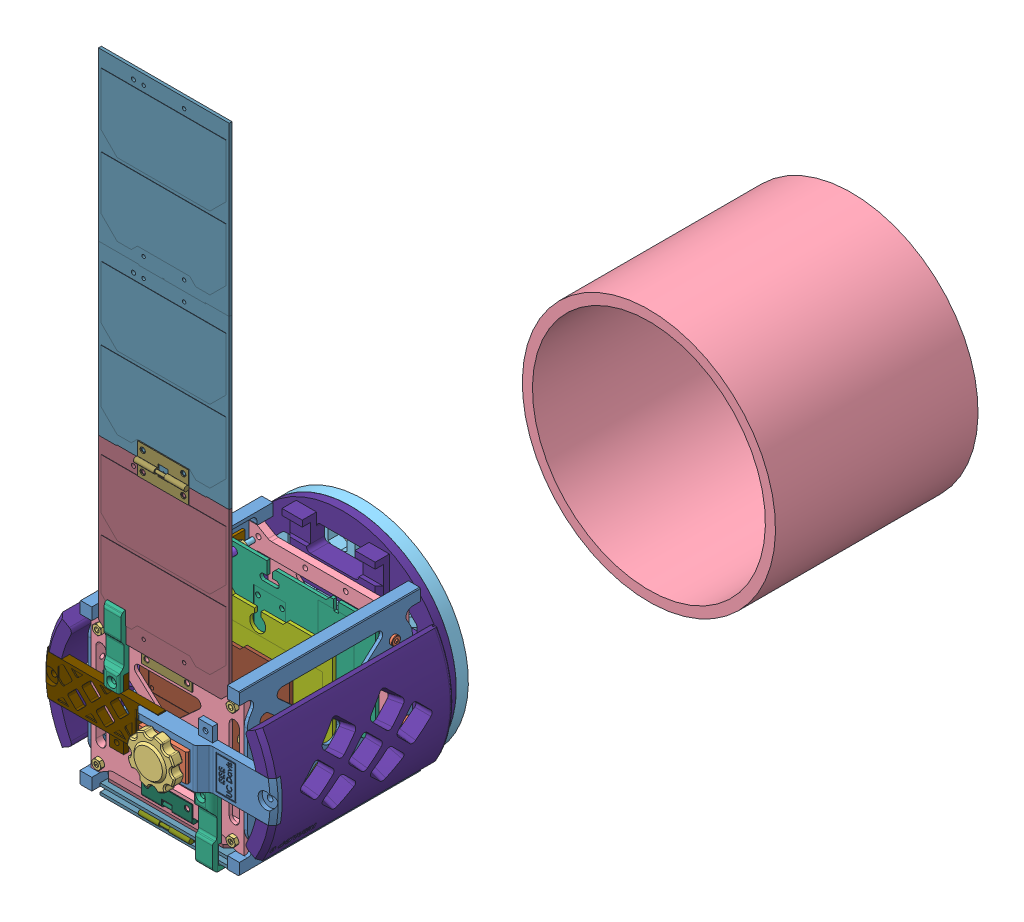
SolidWorks assembly 1U_Chassis, configuration Default. Lengths in mm.
Overall size (181.49 443.8 451.11).
71 component instances, 24 part files, 79 mates.
Components (placement in the parent):
- X-Face-1: X-Face [Default] at (6.5247 99.6979 78.5413) size (7.5 100 113.5)
- X-Face-2: X-Face [Default] at (106.5247 99.6979 78.5413) x (-1 0 0) z (0 0 1) size (7.5 100 113.5)
- 92855A309_18-8 Stainless Steel Low-Profile Socket Head Screws-1: 92855A309_18-8 Stainless Steel Low-Profile Socket Head Screws [92855A309] at (98.5247 117.1979 126.2913) x (0 0 1) z (-1 0 0) size (5.5 5.5 10.17)
- 90685A037_High-Strength Steel Hex Nut-1: 90685A037_High-Strength Steel Hex Nut [90685A037] at (100.3247 117.1979 126.2913) x (0 0 1) z (-1 0 0) size (5.5 6.35 2.69)
- 92855A309_18-8 Stainless Steel Low-Profile Socket Head Screws-2: 92855A309_18-8 Stainless Steel Low-Profile Socket Head Screws [92855A309] at (98.5247 82.1979 126.2913) x (0 0.91884 0.39463) z (-1 0 0) size (5.5 5.5 10.17)
- 90685A037_High-Strength Steel Hex Nut-2: 90685A037_High-Strength Steel Hex Nut [90685A037] at (100.8247 82.1979 126.2913) x (0 -0.924225 -0.381849) z (1 0 0) size (5.5 6.35 2.69)
- 92855A309_18-8 Stainless Steel Low-Profile Socket Head Screws-3: 92855A309_18-8 Stainless Steel Low-Profile Socket Head Screws [92855A309] at (98.5247 117.1979 30.7913) x (0 0.937066 0.349151) z (-1 0 0) size (5.5 5.5 10.17)
- 92855A309_18-8 Stainless Steel Low-Profile Socket Head Screws-4: 92855A309_18-8 Stainless Steel Low-Profile Socket Head Screws [92855A309] at (98.5247 82.1979 30.7913) x (0 0.549538 0.835469) z (-1 0 0) size (5.5 5.5 10.17)
- 90685A037_High-Strength Steel Hex Nut-3: 90685A037_High-Strength Steel Hex Nut [90685A037] at (103.4151 117.1979 30.7913) x (0 0 1) z (-1 0 0) size (5.5 6.35 2.69)
- 90685A037_High-Strength Steel Hex Nut-4: 90685A037_High-Strength Steel Hex Nut [90685A037] at (100.3247 82.1979 30.7913) x (0 0 1) z (-1 0 0) size (5.5 6.35 2.69)
- Z-Face-1: Z-Face [Default] at (56.5247 99.6979 26.7913) x (1 0 0) z (0 -1 0) size (96 8 84.8)
- Z-Face-2: Z-Face [Default] at (56.5247 99.6979 130.2913) x (-1 0 0) z (0 -1 0) size (96 8 84.8)
- 90685A037_High-Strength Steel Hex Nut-5: 90685A037_High-Strength Steel Hex Nut [90685A037] at (14.5247 136.1979 131.4913) x (-0.357096 -0.934068 0) z (0 0 -1) size (5.5 6.35 2.69)
- 90685A037_High-Strength Steel Hex Nut-6: 90685A037_High-Strength Steel Hex Nut [90685A037] at (14.5247 63.1979 131.8682) x (-0.923728 -0.383049 0) z (0 0 -1) size (5.5 6.35 2.69)
- 90685A037_High-Strength Steel Hex Nut-7: 90685A037_High-Strength Steel Hex Nut [90685A037] at (98.5247 136.1979 131.5827) x (-0.923728 -0.383049 0) z (0 0 -1) size (5.5 6.35 2.69)
- 90685A037_High-Strength Steel Hex Nut-8: 90685A037_High-Strength Steel Hex Nut [90685A037] at (98.5247 63.1979 131.646) x (-0.923728 -0.383049 0) z (0 0 -1) size (5.5 6.35 2.69)
- 92855A309_18-8 Stainless Steel Low-Profile Socket Head Screws-5: 92855A309_18-8 Stainless Steel Low-Profile Socket Head Screws [92855A309] at (98.5247 130.1979 38.7913) x (0 -0.400827 -0.916154) z (-1 0 0) size (5.5 5.5 10.17)
- 92855A309_18-8 Stainless Steel Low-Profile Socket Head Screws-6: 92855A309_18-8 Stainless Steel Low-Profile Socket Head Screws [92855A309] at (98.5247 69.1979 38.7913) x (0 0.663174 0.748465) z (-1 0 0) size (5.5 5.5 10.17)
- 90685A037_High-Strength Steel Hex Nut-9: 90685A037_High-Strength Steel Hex Nut [90685A037] at (98.5247 136.1979 41.6536) x (0.999336 0.036432 0) z (0 0 1) size (5.5 6.35 2.69)
- 90685A037_High-Strength Steel Hex Nut-10: 90685A037_High-Strength Steel Hex Nut [90685A037] at (14.5247 136.1979 42.0467) x (-0.999987 -0.005017 0) z (0 0 -1) size (5.5 6.35 2.69)
- 90685A037_High-Strength Steel Hex Nut-11: 90685A037_High-Strength Steel Hex Nut [90685A037] at (14.5247 63.1979 41.6778) x (0.999566 -0.029475 0) z (0 0 1) size (5.5 6.35 2.69)
- 90685A037_High-Strength Steel Hex Nut-12: 90685A037_High-Strength Steel Hex Nut [90685A037] at (98.5247 63.1979 41.599) x (0.999982 0.005949 0) z (0 0 1) size (5.5 6.35 2.69)
- PCB_Stack_3-1: PCB_Stack_3 [Default] at (98.5247 136.1979 34.7913) x (1 -0.000003 0) z (-0.000003 -1 0) size (96 95 83)
  - PCB_Rod_2-1: PCB_Rod_2 [Default] at origin size (3 95 3)
  - PCB_Rod_2-2: PCB_Rod_2 [Default] at (-84 0 0.0003) x (-0.139284 0 0.990253) z (-0.990253 0 -0.139284) size (3 95 3)
  - PCB_Rod_2-3: PCB_Rod_2 [Default] at (-83.9998 0 73.0003) x (0.037489 0 0.999297) z (-0.999297 0 0.037489) size (3 95 3)
  - PCB_Rod_2-4: PCB_Rod_2 [Default] at (0.0002 0 73) x (0.981991 0 -0.188925) z (0.188925 0 0.981991) size (3 95 3)
  - PCB_Battery-1: PCB_Battery [Default] at (-41.9999 10 36.5001) x (-1 0 0.000003) z (-0.000003 0 -1) size (94 2 83)
  - PCB-2: PCB [Default] at (-41.9999 37 36.5001) x (1 0 -0.000003) z (0.000003 0 1) size (94 2 83)
  - Aluminum Unthreaded Spacer_Battery-1: Aluminum Unthreaded Spacer_Battery [94669A105] at (0 24.5 0) x (0.317635 0 -0.948213) z (0 1 0) size (4.5 4.5 25)
  - Aluminum Unthreaded Spacer_Battery-2: Aluminum Unthreaded Spacer_Battery [94669A105] at (0 51.5 0) x (0.317635 0 -0.948213) z (0 1 0) size (4.5 4.5 25)
  - Aluminum Unthreaded Spacer_Battery-3: Aluminum Unthreaded Spacer_Battery [94669A105] at (0 78.5 0) x (-0.841831 0 -0.539741) z (0 1 0) size (4.5 4.5 25)
  - Aluminum Unthreaded Spacer_Battery-4: Aluminum Unthreaded Spacer_Battery [94669A105] at (0.0002 24.5 73) x (0.317635 0 -0.948213) z (0 1 0) size (4.5 4.5 25)
  - Aluminum Unthreaded Spacer_Battery-5: Aluminum Unthreaded Spacer_Battery [94669A105] at (0.0002 51.5 73) x (0.317635 0 -0.948213) z (0 1 0) size (4.5 4.5 25)
  - Aluminum Unthreaded Spacer_Battery-6: Aluminum Unthreaded Spacer_Battery [94669A105] at (0.0002 78.5 73) x (-0.286549 0 -0.958066) z (0 1 0) size (4.5 4.5 25)
  - Aluminum Unthreaded Spacer_Battery-7: Aluminum Unthreaded Spacer_Battery [94669A105] at (-83.9998 24.5 73.0003) x (0.317635 0 -0.948213) z (0 1 0) size (4.5 4.5 25)
  - Aluminum Unthreaded Spacer_Battery-8: Aluminum Unthreaded Spacer_Battery [94669A105] at (-83.9998 51.5 73.0003) x (0.317635 0 -0.948213) z (0 1 0) size (4.5 4.5 25)
  - Aluminum Unthreaded Spacer_Battery-9: Aluminum Unthreaded Spacer_Battery [94669A105] at (-83.9998 78.5 73.0003) x (-0.883236 0 -0.468929) z (0 1 0) size (4.5 4.5 25)
  - Aluminum Unthreaded Spacer_Battery-10: Aluminum Unthreaded Spacer_Battery [94669A105] at (-84 51.5 0.0003) x (0.317635 0 -0.948213) z (0 1 0) size (4.5 4.5 25)
  - Aluminum Unthreaded Spacer_Battery-11: Aluminum Unthreaded Spacer_Battery [94669A105] at (-84 78.5 0.0003) x (-0.872408 0 -0.488777) z (0 1 0) size (4.5 4.5 25)
  - Aluminum Unthreaded Spacer_Battery-12: Aluminum Unthreaded Spacer_Battery [94669A105] at (-84 24.5 0.0003) x (0.317635 0 -0.948213) z (0 1 0) size (4.5 4.5 25)
  - 88805K144_Architectural 6063 Aluminum 90 Degree Angle-1: 88805K144_Architectural 6063 Aluminum 90 Degree Angle [88805K144] at (-85.2375 5.2375 3.0003) x (-1 0 0.000003) z (0.000003 0 1) size (9.53 9.53 13)
  - 88805K144_Architectural 6063 Aluminum 90 Degree Angle-2: 88805K144_Architectural 6063 Aluminum 90 Degree Angle [88805K144] at (1.2377 5.2375 70) x (0 1 0) z (0.000003 0 1) size (9.53 9.53 13)
  - PCB_Bracket_1_(88805K144_Architectural 6063 Aluminum 90 Degree Angle)-1: PCB_Bracket_1_(88805K144_Architectural 6063 Aluminum 90 Degree Angle) [88805K144] at (1.2375 5.2375 3) x (0 1 0) z (0.000003 0 1) size (9.53 9.53 13)
  - PCB_Bracket_1_(88805K144_Architectural 6063 Aluminum 90 Degree Angle)-2: PCB_Bracket_1_(88805K144_Architectural 6063 Aluminum 90 Degree Angle) [88805K144] at (-85.2373 5.2375 70.0003) x (0 1 0) z (-0.000003 0 -1) size (9.53 9.53 13)
  - PCB2-1: PCB2 [Default] at (-41.9999 64 36.5001) x (1 0 -0.000003) z (0.000003 0 1) size (94 2 83)
- 90685A037_High-Strength Steel Hex Nut-13: 90685A037_High-Strength Steel Hex Nut [90685A037] at (11.3122 130.1979 38.7913) x (0 0.17998 -0.98367) z (1 0 0) size (5.5 6.35 2.69)
- COTS_OPEN-1: COTS_OPEN [Default] at (85.632 135.5476 144.7949) x (0 1 0) z (-1 0 0) size (322.55 8.13 82)
  - COTS_STS1114_180-1: COTS_STS1114_180 [Default] at (-5.3531 13.9448 13.2324) size (19.13 3.17 31.75)
  - SP_Imperial_COTS_Hinge_BASE-1: SP_Imperial_COTS_Hinge_BASE [Default] at (54.6417 13.9448 29.1074) x (-1 0 0) z (0 -1 0) size (105.41 82 1.98)
  - COTS_STS1114_180-2: COTS_STS1114_180 [Default] at (116.6685 12.1668 13.2324) x (-1 0 0) z (0 0 1) size (19.13 3.17 31.75)
  - Solar_Panel_FULL_Imperial_COTS_Hinge-1: Solar_Panel_FULL_Imperial_COTS_Hinge [Default] at (159.5691 13.9448 29.1074) x (-1 0 0) z (0 -1 0) size (105.41 82 1.98)
  - COTS_STS1114_180-3: COTS_STS1114_180 [Default] at (202.4697 13.9448 13.2324) size (19.13 3.17 31.75)
  - Solar_Panel_FULL_Imperial_COTS_Hinge-2: Solar_Panel_FULL_Imperial_COTS_Hinge [Default] at (264.4965 13.9448 29.1074) x (-1 0 0) z (0 -1 0) size (105.41 82 1.98)
- COTS_CLOSED-1: COTS_CLOSED [Default] at (82.4423 68.1791 105.3111) x (0 -1 0) z (-1 0 0) size (23.06 108.15 82)
  - COTS_STS1114_90-1: COTS_STS1114_90 [Default] at (8.5663 23.9515 10.0426) size (11.18 11.18 31.75)
  - SP_Imperial_COTS_Hinge_BASE-1: SP_Imperial_COTS_Hinge_BASE [Default] at (10.1538 -26.5056 25.9176) x (0 1 0) z (1 0 0) size (105.41 82 1.98)
  - COTS_STS1114_0-1: COTS_STS1114_0 [Default] at (13.5193 -78.9947 41.7926) x (1 0 0) z (0 0 -1) size (3.17 11.18 31.75)
  - Solar_Panel_FULL_Imperial_COTS_Hinge-1: Solar_Panel_FULL_Imperial_COTS_Hinge [Default] at (16.8848 -26.5056 25.9176) x (0 -1 0) z (-1 0 0) size (105.41 82 1.98)
  - COTS_STS1114_0-2: COTS_STS1114_0 [Default] at (18.4723 25.9835 10.0426) size (3.17 11.18 31.75)
  - Solar_Panel_FULL_Imperial_COTS_Hinge-2: Solar_Panel_FULL_Imperial_COTS_Hinge [Default] at (20.0598 -26.5056 25.9176) x (0 1 0) z (1 0 0) size (105.41 82 1.98)
- MountyThingy-1: MountyThingy [Default] at (56.5247 99.694 26.7913) x (0 -1 0) z (0 0 -1) size (132.08 144.9 120.51)
- ClampThingy-1: ClampThingy [Default] at (-5.4785 91.3199 190.3884) x (0 1 0) z (0 0 -1) size (43.18 145.58 21.82)
  - MountyThingyTop2-1: MountyThingyTop2 [Default] at (8.374 61.2013 54.5171) size (43.18 72.39 10.16)
  - MountyThingyTop1-1: MountyThingyTop1 [Default] at (8.374 62.0032 54.5171) size (43.18 83.94 10.16)
  - Wedge-1: Wedge [Default] at (-0.262 71.7622 52.1294) x (0 -1 0) z (1 0 0) size (30.86 5.08 17.27)
  - ThumbScrew-1: ThumbScrew [Default] at (8.374 72.1632 45.3984) x (-0.6464 0.762999 0) z (0 0 -1) size (29.63 29.63 12.45)
- Rochet-1: Rochet [Default] at (56.5247 99.694 -298.4986) x (0.987856 -0.155371 0) z (0 0 1) size (158.75 158.75 127)
- Insulator-1: Insulator [Default] at (56.5247 99.694 7.7413) x (-1 0 0) z (0 1 0) size (132.08 7.62 132.08)
- SolarPanelClamp-1: SolarPanelClamp [Default] at (79.532 78.104 130.7913) x (0 1 0) z (1 0 0) size (43.7 10.79 11.43)
- SolarPanelClamp-2: SolarPanelClamp [Default] at (32.7155 121.284 130.7913) x (0 -1 0) z (-1 0 0) size (43.7 10.79 11.43)
Mates (geometry in assembly coordinates):
- Coincident2: coincident anti-aligned: plane of X-Face-1 through (8.5247 57.1979 135.2913) normal (1 0 0); plane of S2-1 through (8.5247 142.1979 184.9271) normal (-1 0 0)
- Coincident3: coincident anti-aligned: plane of X-Face-1 through (8.5247 142.1979 135.2913) normal (0 -1 0); plane of S2-1 through (56.5247 142.1979 135.6771) normal (0 1 0)
- Coincident5: coincident anti-aligned: plane of S2-1 through (56.5247 142.1979 135.6771) normal (0 1 0); plane of X-Face-2 through (99.0247 142.1979 135.2913) normal (0 -1 0)
- Coincident6: coincident anti-aligned: plane of S2-1 through (104.5247 142.1979 184.9271) normal (1 0 0); plane of X-Face-2 through (104.5247 142.1979 135.2913) normal (-1 0 0)
- Coincident8: coincident anti-aligned: plane of X-Face-1 through (14.0247 57.1979 135.2913) normal (0 1 0); plane of S2-2 through (56.5247 57.1979 135.1691) normal (0 -1 0)
- Coincident9: coincident anti-aligned: plane of X-Face-1 through (8.5247 57.1979 135.2913) normal (1 0 0); plane of S2-2 through (8.5247 59.1979 184.4191) normal (-1 0 0)
- Coincident14: coincident aligned: plane of X-Face-1 through (14.0247 149.6979 135.2913) normal (0 1 0); plane of X-Face-2 through (106.5247 149.6979 135.2913) normal (0 1 0)
- Coincident16: coincident anti-aligned: plane of X-Face-1 through (8.5247 57.1979 135.2913) normal (1 0 0); plane of Z-2 through (8.5247 57.1979 130.2913) normal (-1 0 0)
- Coincident17: coincident aligned: plane of X-Face-1 through (6.5247 99.6979 130.2913) normal (0 0 1); plane of Z-2 through (104.5247 57.1979 130.2913) normal (0 0 1)
- Coincident18: coincident anti-aligned: plane of X-Face-1 through (14.0247 57.1979 135.2913) normal (0 1 0); plane of Z-2 through (56.5247 57.1979 128.2913) normal (0 -1 0)
- Concentric5: concentric aligned: cylinder of X-Face-2 through (106.5247 117.1979 126.2913) axis (-1 0 0) radius 1.5; cylinder of 92855A309_18-8 Stainless Steel Low-Profile Socket Head Screws-1 through (108.5247 117.1979 126.2913) axis (-1 0 0) radius 2.75
- Coincident19: coincident anti-aligned: plane of X-Face-2 through (106.5247 49.6979 135.2913) normal (1 0 0); plane of 92855A309_18-8 Stainless Steel Low-Profile Socket Head Screws-1 through (106.5247 117.1979 126.2913) normal (-1 0 0)
- Coincident21: coincident anti-aligned: circle of Z-2; circle of 90685A037_High-Strength Steel Hex Nut-1
- Concentric6: concentric aligned: circle of S1-2; circle of 92855A309_18-8 Stainless Steel Low-Profile Socket Head Screws-2
- Concentric7: concentric aligned: cylinder of X-Face-2 through (106.5247 82.1979 126.2913) axis (-1 0 0) radius 1.5; cylinder of 92855A309_18-8 Stainless Steel Low-Profile Socket Head Screws-2 through (108.5247 82.1979 126.2913) axis (-1 0 0) radius 2.75
- Coincident22: coincident anti-aligned: plane of X-Face-2 through (106.5247 49.6979 135.2913) normal (1 0 0); plane of 92855A309_18-8 Stainless Steel Low-Profile Socket Head Screws-2 through (106.5247 82.1979 126.2913) normal (-1 0 0)
- Coincident23: coincident anti-aligned: circle of Z-2; circle of 90685A037_High-Strength Steel Hex Nut-2
- Concentric8: concentric aligned: cylinder of X-Face-2 through (106.5247 117.1979 30.7913) axis (-1 0 0) radius 1.5; cylinder of 92855A309_18-8 Stainless Steel Low-Profile Socket Head Screws-3 through (108.5247 117.1979 30.7913) axis (-1 0 0) radius 2.75
- Coincident24: coincident anti-aligned: plane of X-Face-2 through (104.5247 142.1979 135.2913) normal (-1 0 0); plane of Z-2 through (104.5247 57.1979 120.7913) normal (1 0 0)
- Coincident25: coincident anti-aligned: plane of X-Face-2 through (106.5247 49.6979 135.2913) normal (1 0 0); plane of 92855A309_18-8 Stainless Steel Low-Profile Socket Head Screws-3 through (106.5247 117.1979 30.7913) normal (-1 0 0)
- Concentric9: concentric aligned: cylinder of X-Face-2 through (106.5247 82.1979 30.7913) axis (-1 0 0) radius 1.5; cylinder of 92855A309_18-8 Stainless Steel Low-Profile Socket Head Screws-4 through (108.5247 82.1979 30.7913) axis (-1 0 0) radius 2.75
- Coincident26: coincident anti-aligned: plane of X-Face-2 through (106.5247 49.6979 135.2913) normal (1 0 0); plane of 92855A309_18-8 Stainless Steel Low-Profile Socket Head Screws-4 through (106.5247 82.1979 30.7913) normal (-1 0 0)
- Coincident27: coincident anti-aligned: plane of X-Face-2 through (104.5247 142.1979 135.2913) normal (-1 0 0); plane of Z-Face-1 through (104.5247 57.2979 28.7913) normal (1 0 0)
- Distance1: distance = 0 mm aligned: plane of Z-Face-1 through (90.534 57.8699 26.7913) normal (0 0 -1); plane of X-Face-2 through (106.5247 99.6979 26.7913) normal (0 0 -1)
- Coincident34: coincident aligned: plane of X-Face-1 through (6.5247 99.6979 26.7913) normal (0 0 -1); plane of Z-Face-1 through (90.534 57.8699 26.7913) normal (0 0 -1)
- Coincident35: coincident: plane of Z-Face-1 through (90.534 57.8699 26.7913) normal (0 0 -1); plane of Hinge_Assembly-2/H2-3 through (44.0247 128.9479 26.7913) normal (0 0 1)
- Coincident36: coincident: cylinder of Z-Face-1 through (43.8247 133.7759 28.7913) axis (0 0 -1) radius 1.5; circle of Hinge_Assembly-2/H2-3
- Parallel3: parallel aligned: line of Z-Face-1 through (90.534 137.5259 26.7913) axis (-1 0 0); line of Hinge_Assembly-2/H2-3 through (79.0247 128.9479 25.0413) axis (-1 0 0)
- Coincident42: coincident anti-aligned: plane of X-Face-1 through (8.5247 57.1979 135.2913) normal (1 0 0); plane of Z-Face-2 through (8.5247 57.2979 128.2913) normal (-1 0 0)
- Coincident43: coincident aligned: plane of X-Face-1 through (6.5247 99.6979 130.2913) normal (0 0 1); plane of Z-Face-2 through (22.5154 57.8699 130.2913) normal (0 0 1)
- Concentric12: concentric anti-aligned: circle of 90685A037_High-Strength Steel Hex Nut-3; circle of Z2-1
- Concentric14: concentric aligned: circle of Z2-2; circle of 90685A037_High-Strength Steel Hex Nut-6
- Concentric15: concentric aligned: circle of Z2-2; circle of 90685A037_High-Strength Steel Hex Nut-7
- Concentric16: concentric aligned: circle of Z2-2; circle of 90685A037_High-Strength Steel Hex Nut-8
- Coincident50: coincident anti-aligned: plane of X-Face-2 through (106.5247 49.6979 135.2913) normal (1 0 0); plane of 92855A309_18-8 Stainless Steel Low-Profile Socket Head Screws-5 through (106.5247 130.1979 38.7913) normal (-1 0 0)
- Coincident51: coincident anti-aligned: plane of X-Face-2 through (106.5247 49.6979 135.2913) normal (1 0 0); plane of 92855A309_18-8 Stainless Steel Low-Profile Socket Head Screws-6 through (106.5247 69.1979 38.7913) normal (-1 0 0)
- Concentric24: concentric aligned: circle of Z-Face-2; circle of 90685A037_High-Strength Steel Hex Nut-5
- Coincident64: coincident anti-aligned: plane of Z-Face-2 through (22.5154 57.8699 130.2913) normal (0 0 1); plane of 90685A037_High-Strength Steel Hex Nut-5 through (14.5247 136.1979 130.2913) normal (0 0 -1)
- Concentric25: concentric anti-aligned: cylinder of X-Face-1 through (6.5247 117.1979 126.2913) axis (1 0 0) radius 1.5; cylinder of Z-Face-2 through (13.5247 117.1979 126.2913) axis (-1 0 0) radius 1.5
- Concentric26: concentric anti-aligned: cylinder of Z-Face-2 through (98.5247 63.1979 128.2913) axis (0 0 1) radius 1.5875; cylinder of PCB_Stack_3-1/PCB_Rod_2-4 through (98.5247 63.1979 129.7913) axis (0 0 -1) radius 1.5
- Coincident67: coincident anti-aligned: plane of Z-Face-2 through (56.5247 99.6979 125.7913) normal (0 0 -1); plane of PCB_Stack_3-1/Aluminum Unthreaded Spacer_Battery-3 through (98.5247 136.1979 125.7913) normal (0 0 1)
- Parallel10: parallel anti-aligned: line of X-Face-2 through (104.5247 119.8573 34.7913) axis (0 -1 0); line of PCB_Stack_3-1/PCB_Battery-1 through (103.5247 58.1979 46.7913) axis (0 1 0)
- Concentric27: concentric anti-aligned: circle of 90685A037_High-Strength Steel Hex Nut-10; circle of PCB_Stack_3-1/88805K144_Architectural 6063 Aluminum 90 Degree Angle-1
- Concentric28: concentric anti-aligned: circle of PCB_Stack_3-1/88805K144_Architectural 6063 Aluminum 90 Degree Angle-1; circle of 90685A037_High-Strength Steel Hex Nut-13
- Coincident68: coincident anti-aligned: plane of PCB_Stack_3-1/88805K144_Architectural 6063 Aluminum 90 Degree Angle-1 through (10.1122 126.6979 35.2663) normal (1 0 0); plane of 90685A037_High-Strength Steel Hex Nut-13 through (10.1122 130.1979 38.7913) normal (-1 0 0)
- Coincident69: coincident anti-aligned: circle of 90685A037_High-Strength Steel Hex Nut-9; cylinder of PCB_Stack_3-1/PCB_Rod_2-1 through (98.5247 136.1979 129.7913) axis (0 0 -1) radius 1.5
- Coincident70: coincident anti-aligned: circle of 90685A037_High-Strength Steel Hex Nut-12; cylinder of PCB_Stack_3-1/PCB_Rod_2-4 through (98.5247 63.1979 129.7913) axis (0 0 -1) radius 1.5
- Coincident71: coincident anti-aligned: circle of 90685A037_High-Strength Steel Hex Nut-11; cylinder of PCB_Stack_3-1/PCB_Rod_2-3 through (14.5247 63.1979 129.7913) axis (0 0 -1) radius 1.5
- Concentric29: concentric aligned: circle of X-Face-2; circle of 92855A309_18-8 Stainless Steel Low-Profile Socket Head Screws-5
- Concentric30: concentric aligned: circle of X-Face-2; circle of 92855A309_18-8 Stainless Steel Low-Profile Socket Head Screws-6
- Coincident72: coincident anti-aligned: plane of Z-Face-2 through (22.5154 57.8699 130.2913) normal (0 0 1); plane of COTS_OPEN-1/COTS_STS1114_180-1 through (40.6497 130.1945 130.2913) normal (0 0 -1)
- Concentric31: concentric aligned: cylinder of Z-Face-2 through (43.8247 133.7759 128.2913) axis (0 0 1) radius 1.5; circle of COTS_OPEN-1/COTS_STS1114_180-1
- Parallel11: parallel aligned: line of Z-Face-2 through (22.5154 137.5259 130.2913) axis (1 0 0); line of COTS_OPEN-1/COTS_STS1114_180-1 through (40.6497 130.1945 130.8501) axis (1 0 0)
- Coincident74: coincident anti-aligned: plane of Z-Face-2 through (22.5154 57.8699 130.2913) normal (0 0 1); plane of COTS_CLOSED-1/COTS_STS1114_90-1 through (40.6497 69.2013 130.2913) normal (0 0 -1)
- Concentric32: concentric aligned: cylinder of Z-Face-2 through (43.8247 65.6199 128.2913) axis (0 0 1) radius 1.5; circle of COTS_CLOSED-1/COTS_STS1114_90-1
- Parallel12: parallel anti-aligned: line of Z-Face-2 through (90.534 61.8699 130.2913) axis (-1 0 0); line of COTS_CLOSED-1/COTS_STS1114_90-1 through (40.6497 69.2013 130.8501) axis (1 0 0)
- Coincident75: coincident anti-aligned: plane of X-Face-1 through (8.5247 57.1979 135.2913) normal (1 0 0); plane of Z-Face-1 through (8.5247 57.2979 28.7913) normal (-1 0 0)
- Concentric33: concentric anti-aligned: cylinder of X-Face-1 through (6.5247 117.1979 30.7913) axis (1 0 0) radius 1.5; cylinder of Z-Face-1 through (13.5247 117.1979 30.7913) axis (-1 0 0) radius 1.5
- Coincident76: coincident anti-aligned: plane of X-Face-1 through (6.5247 49.6979 135.2913) normal (0 -1 0); plane of 88805K144_Architectural 6063 Aluminum 90 Degree Angle (1)-1 through (14.4622 49.6979 142.4093) normal (0 1 0)
- Coincident77: coincident anti-aligned: plane of X-Face-1 through (6.5247 149.6979 135.2913) normal (-1 0 0); plane of 88805K144_Architectural 6063 Aluminum 90 Degree Angle (1)-1 through (6.5247 49.6979 142.4093) normal (1 0 0)
- Coincident79: coincident: plane of X-Face-2 through (106.5247 149.6979 135.2913) normal (0 1 0); plane of 88805K144_Architectural 6063 Aluminum 90 Degree Angle (1)-2 through (98.5872 149.6979 154.433) normal (0 -1 0)
- Coincident80: coincident anti-aligned: plane of X-Face-2 through (106.5247 49.6979 135.2913) normal (1 0 0); plane of 88805K144_Architectural 6063 Aluminum 90 Degree Angle (1)-2 through (106.5247 149.6979 154.433) normal (-1 0 0)
- Coincident81: coincident anti-aligned: plane of Z-Face-1 through (90.534 57.8699 26.7913) normal (0 0 -1); plane of MountyThingy-1 through (42.5547 57.9999 26.7913) normal (0 0 1)
- Coincident82: coincident: point of MountyThingy-1; point of MountyThingyTop-1
- Concentric35: concentric anti-aligned: circle of MountyThingy-1; circle of MountyThingyTop-1
- Concentric36: concentric anti-aligned: circle of MountyThingy-1; circle of ClampThingy-1/MountyThingyTop1-1
- Coincident89: coincident anti-aligned: plane of MountyThingy-1 through (56.5247 99.694 130.7913) normal (0 0 1); plane of ClampThingy-1/MountyThingyTop1-1 through (56.5247 99.694 130.7913) normal (0 0 -1)
- Parallel14: parallel anti-aligned: line of MountyThingy-1 through (117.4184 112.521 135.8713) axis (1 0 0); line of ClampThingy-1/MountyThingyTop1-1 through (125.2104 112.394 135.8713) axis (-1 0 0)
- Concentric37: concentric anti-aligned: cylinder of MountyThingy-1 through (56.5247 99.694 20.4413) axis (0 0 1) radius 72.39; cylinder of Rochet-1 through (56.5247 99.694 -171.4986) axis (0 0 -1) radius 73.025
- Parallel16: parallel anti-aligned: line of Z-Face-1 through (90.534 137.5259 31.2913) axis (-1 0 0); line of MountyThingy-1 through (42.5547 138.8481 26.7913) axis (1 0 0)
- Coincident90: coincident anti-aligned: circle of MountyThingy-1; circle of Insulator-1
- Parallel17: parallel aligned: line of MountyThingy-1 through (18.4247 103.9398 15.3613) axis (0 -1 0); line of Insulator-1 through (25.483 88.5333 7.7413) axis (0 -1 0)
- Concentric38: concentric aligned: cylinder of Z-Face-1 through (43.8247 65.6199 28.7913) axis (0 0 -1) radius 1.5; circle of MountyThingy-1
- Concentric39: concentric anti-aligned: cylinder of ClampThingy-1/MountyThingyTop1-1 through (83.977 82.549 133.9663) axis (0 0 -1) radius 1.524; cylinder of SolarPanelClamp-1 through (83.977 82.549 126.3463) axis (0 0 1) radius 1.524
- Coincident92: coincident anti-aligned: plane of ClampThingy-1/MountyThingyTop1-1 through (88.422 86.994 133.9663) normal (1 0 0); plane of SolarPanelClamp-1 through (88.422 78.104 130.7913) normal (-1 0 0)
- Coincident93: coincident anti-aligned: plane of ClampThingy-1/MountyThingyTop1-1 through (56.5247 99.694 133.9663) normal (0 0 1); plane of SolarPanelClamp-1 through (90.962 78.104 133.9663) normal (0 0 -1)
- Concentric40: concentric anti-aligned: cylinder of ClampThingy-1/MountyThingyTop2-1 through (28.2705 116.839 133.9663) axis (0 0 -1) radius 1.524; cylinder of SolarPanelClamp-2 through (28.2705 116.839 126.3463) axis (0 0 1) radius 1.524
- Parallel18: parallel anti-aligned: line of ClampThingy-1/MountyThingyTop2-1 through (23.8255 112.394 130.7913) axis (0 1 0); line of SolarPanelClamp-2 through (21.2855 141.363 130.7913) axis (0 -1 0)
- Coincident95: coincident anti-aligned: plane of ClampThingy-1/MountyThingyTop2-1 through (55.7228 99.694 133.9663) normal (0 0 1); plane of SolarPanelClamp-2 through (21.2855 121.284 133.9663) normal (0 0 -1)
